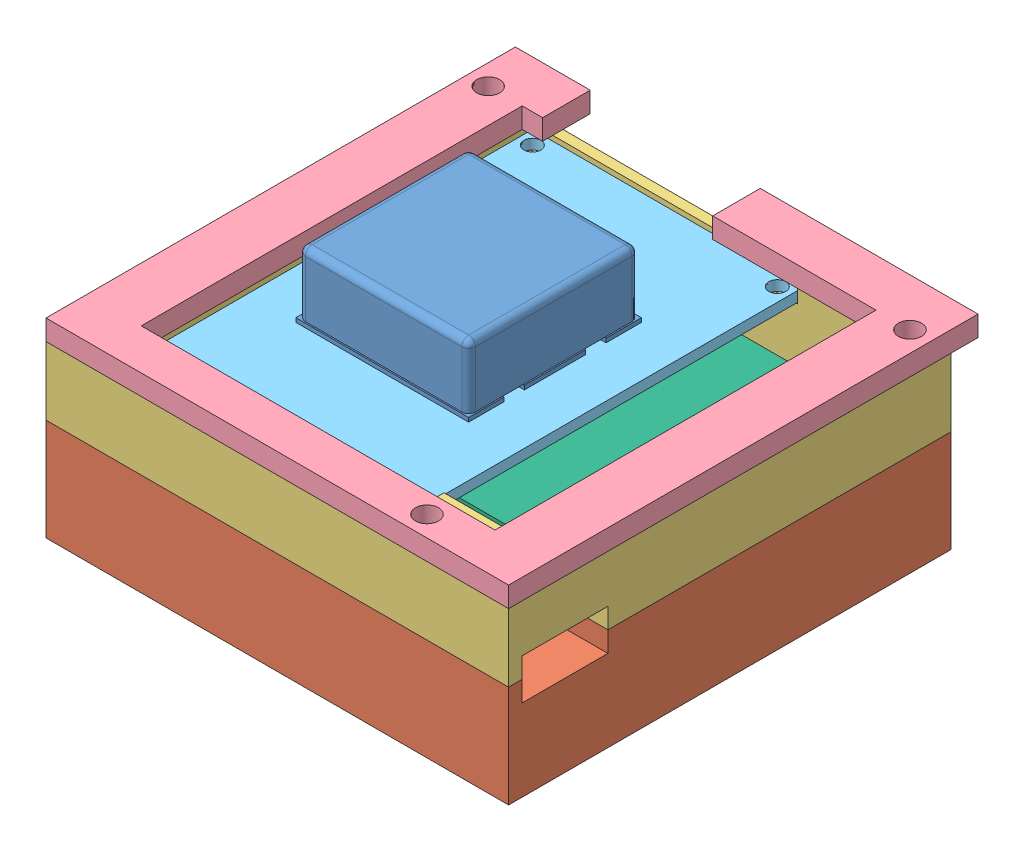
SolidWorks assembly HEL-03-03000-00, configuration Default. Lengths in mm.
Overall size (68 34.4 69).
6 component instances, 6 part files, 15 mates.
Components (placement in the parent):
- HEL-06-03004-00-1: HEL-06-03004-00 [Default] at (-11.5739 17.3489 56.487) size (25.4 14 25.4)
- HEL-04-04000-00-1: HEL-04-04000-00 [Standard] at origin size (68 15 65)
- HEL-04-04001-00-1: HEL-04-04001-00 [Standard] at origin size (68 10 65)
- HEL-04-04002-00-1: HEL-04-04002-00 [Standard] at origin size (68 3 69)
- HEL-06-04000-00-1: HEL-06-04000-00 [Standard] at origin size (40 1.5 60)
- HEL-06-04001-00-1: HEL-06-04001-00 [Standard] at origin size (55 2.5 45)
Mates (geometry in assembly coordinates):
- Coincident5: coincident aligned: plane of HEL-04-04000-00-1 through (-39.6989 7.8489 90.487) normal (-1 0 0); plane of HEL-04-04001-00-1 through (-39.6989 17.8489 90.487) normal (-1 0 0)
- Coincident6: coincident aligned: plane of HEL-04-04000-00-1 through (-39.6989 7.8489 25.487) normal (0 0 -1); plane of HEL-04-04001-00-1 through (-39.6989 17.8489 25.487) normal (0 0 -1)
- Coincident7: coincident anti-aligned: plane of HEL-04-04000-00-1 through (-39.6989 7.8489 90.487) normal (0 1 0); plane of HEL-04-04001-00-1 through (-39.6989 7.8489 90.487) normal (0 -1 0)
- Coincident8: coincident anti-aligned: plane of HEL-04-04001-00-1 through (-39.6989 17.8489 90.487) normal (0 1 0); plane of HEL-04-04002-00-1 through (-39.6989 17.8489 90.487) normal (0 -1 0)
- Coincident9: coincident aligned: plane of HEL-04-04001-00-1 through (-39.6989 17.8489 90.487) normal (-1 0 0); plane of HEL-04-04002-00-1 through (-39.6989 20.8489 90.487) normal (-1 0 0)
- Coincident10: coincident aligned: plane of HEL-04-04001-00-1 through (-39.6989 17.8489 90.487) normal (0 0 1); plane of HEL-04-04002-00-1 through (-39.6989 20.8489 90.487) normal (0 0 1)
- Distance1: distance = 0.25 mm anti-aligned: plane of HEL-04-04003-00-1 through (8.5511 17.3489 87.237) normal (0 0 1); plane of HEL-04-04001-00-1 through (-31.6989 15.8489 87.487) normal (0 0 -1)
- Distance2: distance = 0.25 mm anti-aligned: plane of HEL-04-04001-00-1 through (8.8011 15.8489 26.987) normal (-1 0 0); plane of HEL-04-04003-00-1 through (8.5511 17.3489 87.237) normal (1 0 0)
- Coincident14: coincident anti-aligned: plane of HEL-04-04001-00-1 through (-39.6989 15.8489 90.487) normal (0 1 0); plane of HEL-04-04003-00-1 through (8.5511 15.8489 87.237) normal (0 -1 0)
- Distance3: distance = 7.625 mm aligned: plane of HEL-04-04003-00-1 through (8.5511 17.3489 87.237) normal (1 0 0); plane of HEL-06-03004-00-1 through (0.9261 27.8489 43.987) normal (1 0 0)
- Distance4: distance = 18.5 mm aligned: plane of HEL-06-03004-00-1 through (0.9261 27.8489 43.987) normal (0 0 -1); plane of HEL-04-04001-00-1 through (-39.6989 17.8489 25.487) normal (0 0 -1)
- Coincident17: coincident anti-aligned: plane of HEL-06-03004-00-1 through (-23.5739 17.3489 63.487) normal (0 -1 0); plane of HEL-04-04003-00-1 through (8.5511 17.3489 87.237) normal (0 1 0)
- Distance5: distance = 9 mm aligned: plane of HEL-04-04003-00-1 through (8.5511 17.3489 87.237) normal (0 1 0); plane of HEL-04-04004-00-1 through (-33.1989 8.3489 72.987) normal (0 1 0)
- Distance6: distance = 17.5 mm aligned: plane of HEL-04-04004-00-1 through (-33.1989 7.3489 72.987) normal (0 0 1); plane of HEL-04-04000-00-1 through (-39.6989 7.8489 90.487) normal (0 0 1)
- Distance7: distance = 10.5 mm aligned: plane of HEL-04-04004-00-1 through (17.8011 8.3489 28.987) normal (1 0 0); plane of HEL-04-04000-00-1 through (28.3011 7.8489 90.487) normal (1 0 0)
